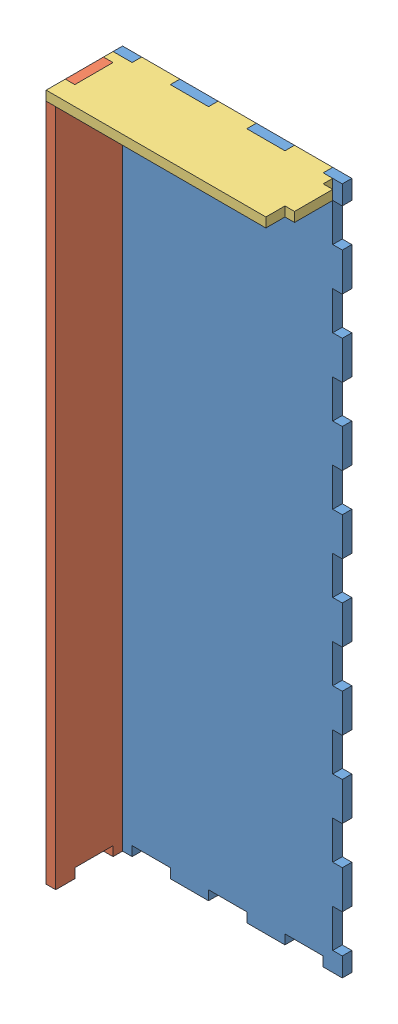
SolidWorks assembly Assem1, configuration Default. Lengths in mm.
Overall size (76.2 228.6 25.4).
3 component instances, 3 part files, 6 mates.
Components (placement in the parent):
- 9x3 bottom-1: 9x3 bottom [Default] at origin size (76.2 228.6 3.17)
- 9x1 side-1: 9x1 side [Default] at (0 0 25.4) x (0 0 -1) z (1 0 0) size (25.4 228.6 3.17)
- 3x1 side-1: 3x1 side [Default] at (0 228.6 25.4) x (0 0 -1) z (0 -1 0) size (25.4 76.2 3.17)
Mates (geometry in assembly coordinates):
- Coincident1: coincident aligned: plane of ?; plane of ?
- Coincident2: coincident aligned: plane of ?; plane of ?
- Coincident3: coincident aligned: plane of ?; plane of ?
- Coincident4: coincident aligned: plane of ?; plane of ?
- Coincident5: coincident aligned: plane of ?; plane of ?
- Coincident6: coincident aligned: plane of ?; plane of ?
